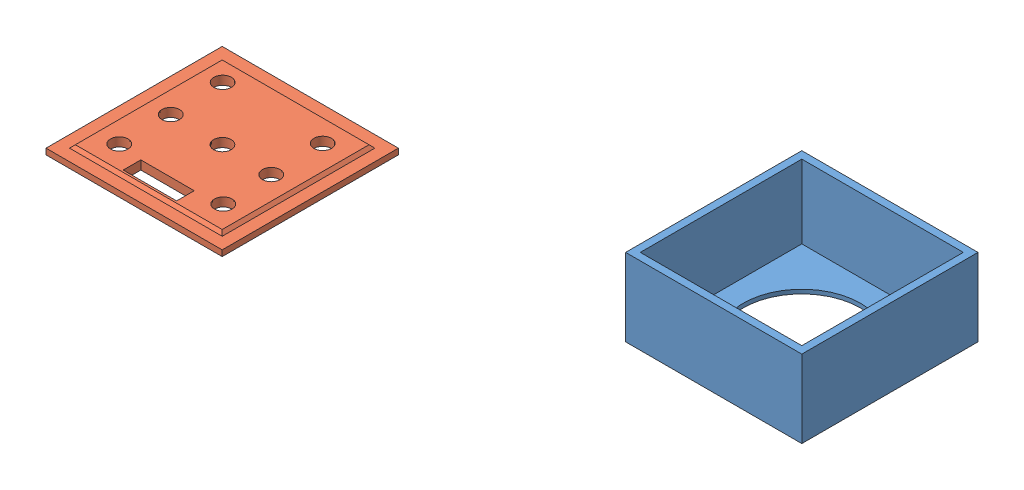
SolidWorks assembly digitalterning, configuration Default. Lengths in mm.
Overall size (182.7 34.13 134.68).
2 component instances, 2 part files, 0 mates.
Components (placement in the parent):
- eske-1: eske [Default] at (1072.1633 -885.9409 106.3092) size (60 26.39 60)
- lokk-1: lokk [Default] at (949.4682 -854.8141 180.9887) size (60 3 60)
